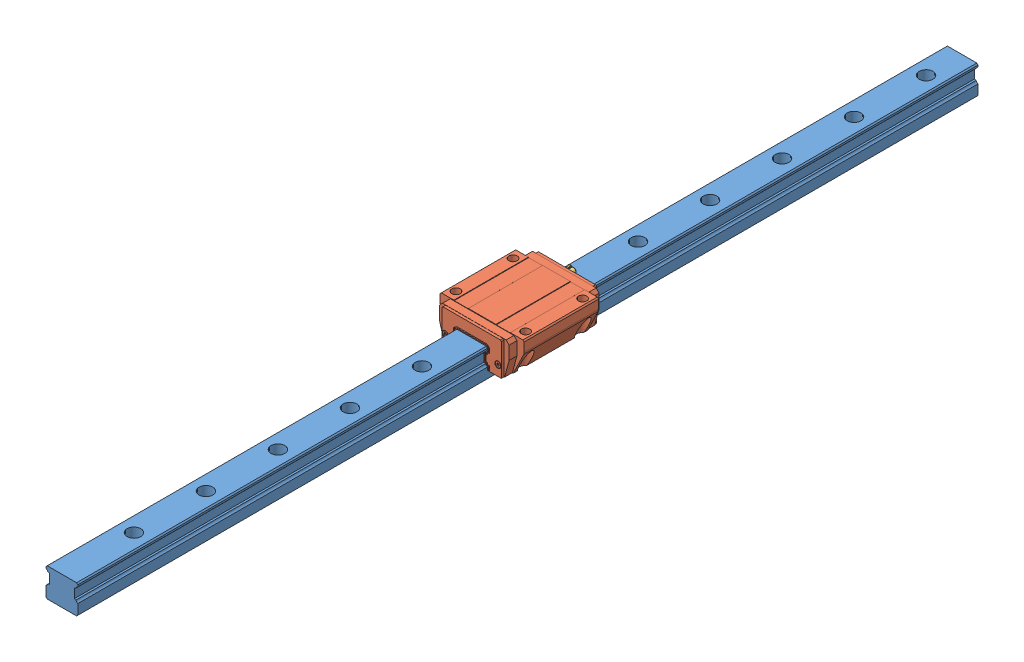
SolidWorks assembly NH55EA_B1_T0_1500_C5_W1_E120_0_FS, configuration Valor predeterminado. Lengths in mm.
Overall size (140 70 1500).
4 component instances, 3 part files, 2 mates.
Components (placement in the parent):
- NH55 Rail-1: NH55 Rail [Valor predeterminado] at origin size (53 48 1500)
- NH55EA_AMBLY_STD-1: NH55EA_AMBLY_STD [Valor predeterminado] at (0 0 799.8028) x (0 0 -1) z (1 0 0) size (174.31 56 140)
  - NH55EA_STD-1: NH55EA_STD [Valor predeterminado] at origin size (159 56 140)
  - B-PT18-1: B-PT18 [Valor predeterminado] at (145 12 0.0012) x (0 -1 0) z (1 0 0) size (11.52 17.05 22.81)
Mates (geometry in assembly coordinates):
- Coincidente1: coincident anti-aligned: plane of NH55 Rail-1 through (-24.4974 0 1500) normal (0 1 0); plane of NH55EA_AMBLY_STD-1/NH55EA_STD-1 through (24.4974 0 675.8028) normal (0 -1 0)
- Largura1: width anti-aligned: plane of NH55EA_AMBLY_STD-1/NH55EA_STD-1 through (-20.7 -9.0316 675.8028) normal (1 0 0); plane of NH55EA_AMBLY_STD-1/NH55EA_STD-1 through (20.7 -24.9679 675.8028) normal (-1 0 0); plane of NH55 Rail-1 through (-20.7 -24.9679 1500) normal (-1 0 0); plane of NH55 Rail-1 through (20.7 -9.0316 1500) normal (1 0 0)
